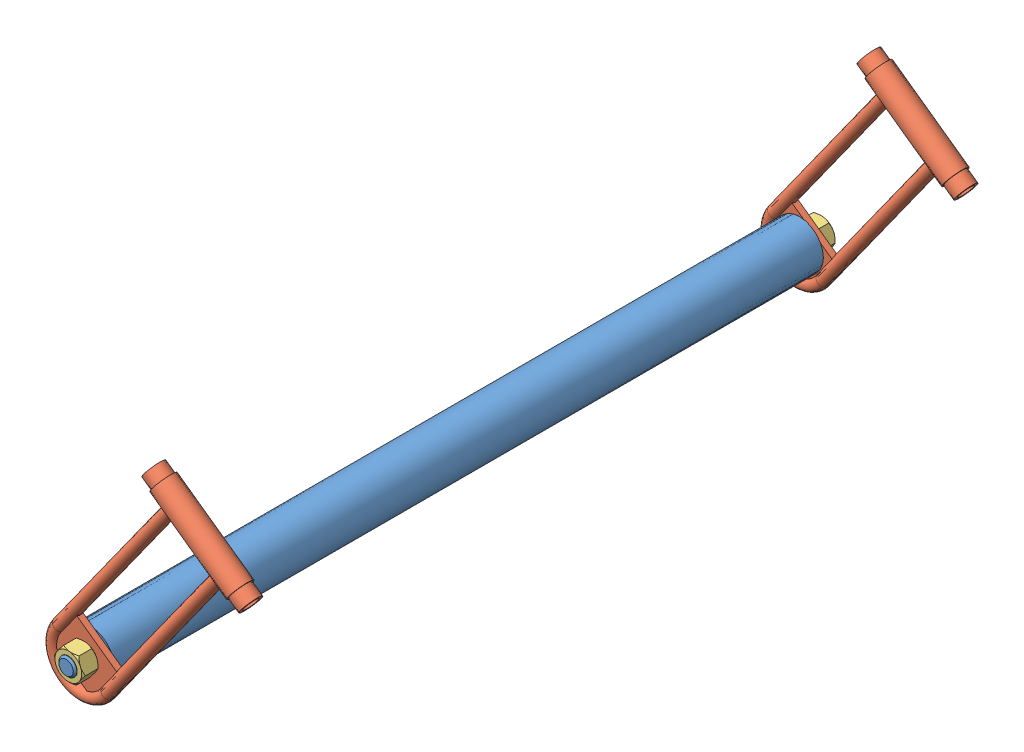
SolidWorks assembly SA1, configuration Default. Lengths in mm.
Overall size (129.23 145.39 403.48).
5 component instances, 3 part files, 22 mates.
Components (placement in the parent):
- SS1-1: SS1 [Default] at (0.7633 27.1847 256.5845) x (1 0 0) z (0 0 1) size (25.4 25.4 403.48)
- SP2-2: SP2 [Default] at (87.3872 94.4048 258.172) x (0.581832 0.813309 0) z (-0.813309 0.581832 0) size (133.34 12.7 63.5)
- SP2-3: SP2 [Default] at (87.3872 94.4048 -122.701) x (0.581832 0.813309 0) z (-0.813309 0.581832 0) size (133.34 12.7 63.5)
- hex nut_ai-3: hex nut_ai [HNUT 0.3750-24-D-N] at (0.7633 27.1846 -132.8483) x (0.910536 0.41343 0) z (0 0 -1) size (14.27 16.48 8.56)
- hex nut_ai-4: hex nut_ai [HNUT 0.3750-24-D-N] at (0.7633 27.1847 268.3193) x (0.910536 0.41343 0) z (0 0 1) size (14.27 16.48 8.56)
Mates (geometry in assembly coordinates):
- Concentric144: concentric: cylinder of SS1-1 through (0.7633 27.1847 256.5845) axis (0 0 -1) radius 4.7625; cylinder of SP2-2 through (0.7633 27.1847 285.7945) axis (0 0 -1) radius 4.7625
- Coincident164: coincident: plane of SS1-1 through (0.7633 27.1847 256.5845) normal (0 0 1); plane of SP2-2 through (51.2356 120.2672 256.5845) normal (0 0 -1)
- Concentric1451: concentric: cylinder of SP2-2 through (30.5071 75.0132 312.8143) axis (0 0 -1) radius 4.7625; cylinder of ? through (30.5071 75.0132 -80.791) axis (0 0 -1) radius 4.7625
- Coincident1651: coincident: plane of SP2-2 through (80.9795 168.0957 286.7793) normal (0 0 1); plane of ? through (33.6641 67.4002 -97.2687) normal (0 0 1)
- Concentric147: concentric: cylinder of SS1-1 through (0.7633 27.1846 -121.1135) axis (0 0 1) radius 4.7625; cylinder of SP2-3 through (0.7633 27.1846 -95.0785) axis (0 0 -1) radius 4.7625
- Coincident167: coincident: plane of SS1-1 through (0.7633 27.1846 -121.1135) normal (0 0 -1); circle of SP2-3
- Concentric1481: concentric: cylinder of SP2-3 through (0.7633 27.1846 -95.0785) axis (0 0 -1) radius 4.7625; cylinder of hex nut_ai-3 through (0.7633 27.1846 -107.8108) axis (0 0 -1) radius 4.7625
- Coincident1691: coincident: plane of SP2-3 through (51.2356 120.2672 -124.2885) normal (0 0 -1); plane of hex nut_ai-3 through (4.1706 19.6804 -124.2885) normal (0 0 1)
- Concentric14821: concentric: cylinder of SP2-3 through (30.5071 75.0132 -68.0587) axis (0 0 -1) radius 4.7625; cylinder of ? through (30.5071 75.0132 -80.791) axis (0 0 -1) radius 4.7625
- Coincident16921: coincident: plane of SP2-3 through (80.9795 168.0957 -97.2687) normal (0 0 -1); plane of ? through (33.6641 67.4002 -97.2687) normal (0 0 1)
- Concentric14831: concentric: cylinder of SP2-2 through (30.5071 75.0132 312.8143) axis (0 0 -1) radius 4.7625; cylinder of ? through (30.5071 75.0132 270.3016) axis (0 0 1) radius 4.7625
- Coincident16931: coincident: plane of SP2-2 through (80.9795 168.0957 286.7793) normal (0 0 1); plane of ? through (30.5071 83.2547 286.7793) normal (0 0 -1)
- Concentric148321: concentric: cylinder of SP2-3 through (0.7633 27.1846 -95.0785) axis (0 0 -1) radius 4.7625; cylinder of hex nut_ai-3 through (0.7633 27.1846 -107.8108) axis (0 0 -1) radius 4.7625
- Coincident169321: coincident: plane of SP2-3 through (51.2356 120.2672 -124.2885) normal (0 0 -1); plane of hex nut_ai-3 through (4.1706 19.6804 -124.2885) normal (0 0 1)
- Concentric148331: concentric: cylinder of SP2-2 through (0.7633 27.1847 285.7945) axis (0 0 -1) radius 4.7625; cylinder of hex nut_ai-4 through (0.7633 27.1847 243.2818) axis (0 0 1) radius 4.7625
- Coincident169331: coincident: plane of SP2-2 through (51.2356 120.2672 259.7595) normal (0 0 1); plane of hex nut_ai-4 through (-2.644 34.6889 259.7595) normal (0 0 -1)
- Parallel1: parallel: plane of SP2-3 through (87.8004 94.1092 -122.701) normal (0.813309 -0.581832 0); plane of hex nut_ai-3 through (8.9658 26.3833 -124.2885) normal (0.813309 -0.581832 0)
- Parallel2: parallel: plane of SP2-2 through (87.8003 94.1092 258.172) normal (0.813309 -0.581832 0); plane of hex nut_ai-4 through (4.1706 19.6804 259.7595) normal (0.813309 -0.581832 0)
- Angle3: planar angle = 0 rad: plane of SP2-3 through (-3.2479 44.1079 -122.701) normal (0.581832 0.813309 0); plane of SP2-2 through (-3.2479 44.1079 258.172) normal (0.581832 0.813309 0)
- Parallel14: parallel: plane of SS1-1 through (-3.4996 19.9703 -131.7994) normal (0 1 0); plane of SP2-3 through (-11.8436 36.8935 -121.6906) normal (0.581832 0.813309 0)
- Angle4: planar angle = 0 rad: plane of SP2-3 through (-3.2479 44.1079 -122.701) normal (0.581832 0.813309 0); plane of SP2-2 through (-3.2479 44.1079 258.172) normal (0.581832 0.813309 0)
- Angle5: planar angle = 0.62098 rad: plane of SP2-3 through (-3.2479 44.1079 -122.701) normal (0.581832 0.813309 0); plane of SS1-1 through (5.0962 27.1846 -132.8098) normal (0 1 0)
